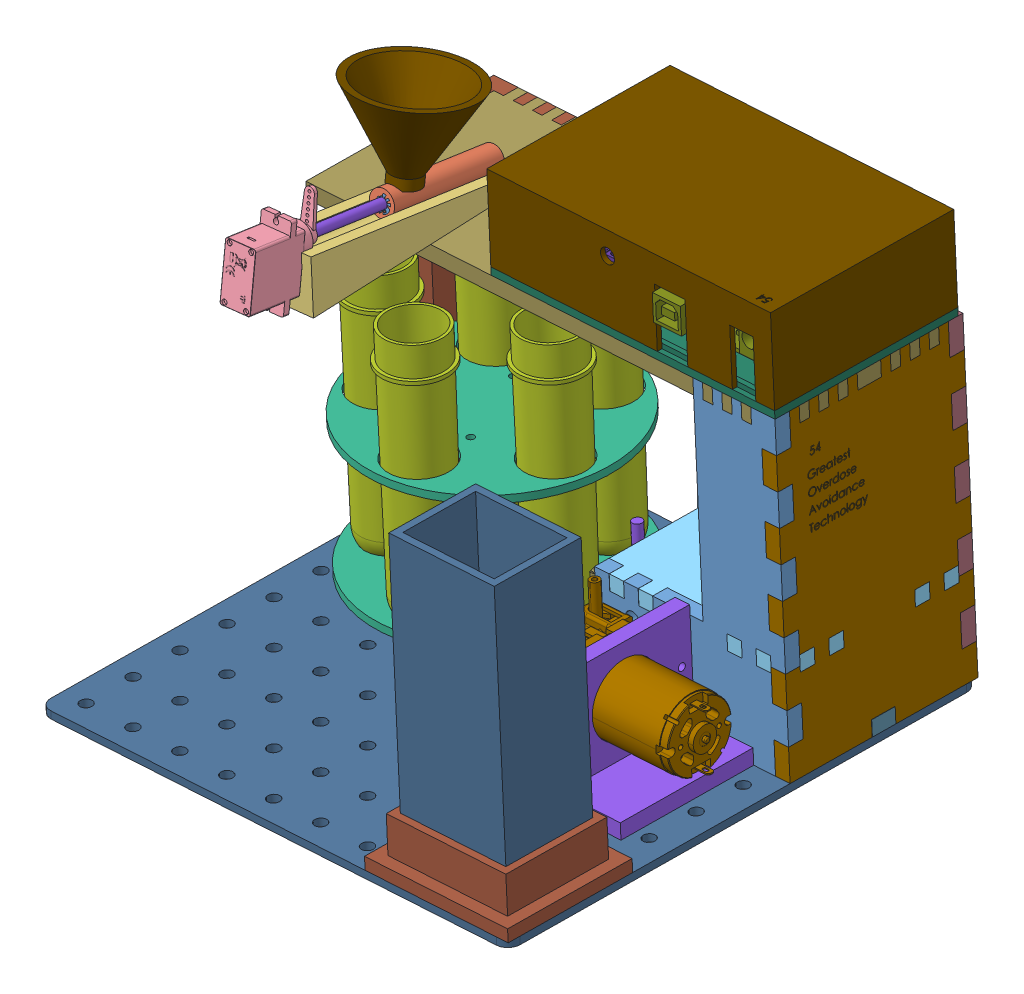
SolidWorks assembly Goat.forEdit4, configuration Default. Lengths in mm.
Overall size (207.7 193.28 201.45).
58 component instances, 40 part files, 115 mates.
Components (placement in the parent):
- 054_10T_NOPRINT_N3-1: 054_10T_NOPRINT_N3 [Default] at (24.5852 63.532 95.5991) x (0.998194 0.060061 -0.000979) z (0.060068 -0.998139 0.010543) size (12 11.58 6) (hidden)
- 054_20T_NOPRINT_N1-1: 054_20T_NOPRINT_N1 [Default] at (17.3412 70.7712 71.3424) x (0.976966 0.060954 0.204504) z (0.060068 -0.998139 0.010543) size (22 22 5.85) (hidden)
- 054_40T_NOPRINT_N2-1: 054_40T_NOPRINT_N2 [Default] at (17.8167 62.8694 71.4259) x (0.478271 0.03805 0.877387) z (0.060068 -0.998139 0.010543) size (42 42 5.85) (hidden)
- 054_50T_NOPRINT_N2-1: 054_50T_NOPRINT_N2 [Default] at (-14.9305 68.9822 85.8339) x (0.998003 0.06026 0.018945) z (0.060068 -0.998139 0.010543) size (52 51.94 5.85) (hidden)
- 054_30T_NOPRINT_N1-1: 054_30T_NOPRINT_N1 [Default] at (-29.6575 61.3354 72.298) x (0.998003 0.06026 0.018945) z (0.060068 -0.998139 0.010543) size (32 31.89 5.85) (hidden)
- DCMotor1-1: DCMotor1 [Default] at (22.0529 105.6116 95.1547) x (0.998194 0.060061 -0.000979) z (0.060068 -0.998139 0.010543) size (24 24 48.5) (hidden)
- 054_Bushing_NOPRINT_n1-1: 054_Bushing_NOPRINT_n1 [Default] at (25.0222 56.2699 95.6758) x (0.998194 0.060061 -0.000979) z (-0.060068 0.998139 -0.010543) size (8 7.5 8) (hidden)
- 054_10T_NOPRINT_N3-2: 054_10T_NOPRINT_N3 [Default] at (-14.5337 62.3892 85.9035) x (0.998003 0.06026 0.018945) z (0.060068 -0.998139 0.010543) size (12 11.58 6) (hidden)
- 054_10T_NOPRINT_N3-3: 054_10T_NOPRINT_N3 [Default] at (-29.2271 54.1839 72.3736) x (0.998003 0.06026 0.018945) z (0.060068 -0.998139 0.010543) size (12 11.58 6) (hidden)
- 054_40T_NOPRINT_N2-2: 054_40T_NOPRINT_N2 [Default] at (-47.3526 53.2765 89.7404) x (0.996292 0.060601 0.061065) z (0.060068 -0.998139 0.010543) size (42 42 5.85) (hidden)
- 054_Shaft_NOPRINT_N4-1: 054_Shaft_NOPRINT_N4 [Default] at (-48.9826 80.3621 89.4543) x (0.996292 0.060601 0.061065) z (0.060068 -0.998139 0.010543) size (4 4 40) (hidden)
- 054_Shaft_NOPRINT_N4-2: 054_Shaft_NOPRINT_N4 [Default] at (-30.8536 81.2115 72.0881) x (0.996135 0.060618 0.06356) z (0.060068 -0.998139 0.010543) size (4 4 40) (hidden)
- 054_Shaft_NOPRINT_N4-3: 054_Shaft_NOPRINT_N4 [Default] at (16.5513 83.8967 71.2038) x (0.998194 0.060061 -0.000979) z (0.060068 -0.998139 0.010543) size (4 4 40) (hidden)
- 054_Shaft_NOPRINT_N4-4: 054_Shaft_NOPRINT_N4 [Default] at (-15.7288 82.2476 85.6938) x (0.996135 0.060618 0.06356) z (0.060068 -0.998139 0.010543) size (4 4 40) (hidden)
- 054_50T_NOPRINT_N2-2: 054_50T_NOPRINT_N2 [Default] at (-88.9036 53.0779 108.5526) x (0.998194 0.060061 -0.000979) z (0.060068 -0.998139 0.010543) size (52 51.94 5.85) (hidden)
- 054_GearboxBack_AC_N1-1: 054_GearboxBack_AC_N1 [Default] at (40.1526 45.813 119.7207) x (0.000317 -0.010543 -0.999944) z (0.060068 -0.998139 0.010543) size (80 6.2 130) (hidden)
- 054_Pegboard_NOPRINT_N1-1: 054_Pegboard_NOPRINT_N1 [Default] at (-153.1553 32.4426 239.8071) x (0.998194 0.060068 -0.000317) z (-0.000317 0.010543 0.999944) size (200 3 200)
- 054_mastwall_AC_N2-1: 054_mastwall_AC_N2 [Default] at (-153.2832 33.6974 74.7786) x (0.000317 -0.010543 -0.999944) z (0.998194 0.060068 -0.000317) size (35 130 6.2)
- 054_topofmast_AC_N1-1: 054_topofmast_AC_N1 [Default] at (-160.7338 157.7415 118.4769) x (0.998194 0.060068 -0.000317) z (-0.000317 0.010543 0.999944) size (200 6.2 80)
- 054_mastwall_AC_N2-2: 054_mastwall_AC_N2 [Default] at (-126.1501 165.1885 38.4049) x (-0.998194 -0.060068 0.000317) z (-0.000317 0.010543 0.999944) size (35 130 6.2)
- 054_bracket_AC_N1-1: 054_bracket_AC_N1 [Default] at (-153.2892 33.6971 74.7846) x (0.998194 0.060068 -0.000317) z (-0.000317 0.010543 0.999944) size (35 6.2 35)
- 054_Peg_NOPRINT_N2-1: 054_Peg_NOPRINT_N2 [Default] at (-143.7859 42.2193 49.6964) x (0.99555 0.060673 0.07211) z (0.072615 -0.006165 -0.997341) size (6 11.2 6) (hidden)
- 054_Peg_NOPRINT_N2-2: 054_Peg_NOPRINT_N2 [Default] at (-123.8283 43.6315 69.6889) x (-0.839619 -0.04481 0.541325) z (0.539845 0.041368 0.840748) size (6 11.2 6) (hidden)
- 054_ArduinoHousingBottom_NOPRINT_N1-1: 054_ArduinoHousingBottom_NOPRINT_N1 [Default] at (-82.2489 168.6753 118.3865) x (0.998194 0.060068 -0.000317) z (-0.000317 0.010543 0.999944) size (121 13 78)
- 054_ArduinoUno_NOPRINT_N1-1: 054_ArduinoUno_NOPRINT_N1 [Default] at (32.4637 187.8519 47.2918) x (-0.006473 -0.010951 -0.999919) z (0.998173 0.059994 -0.007119) size (74.93 14.99 53.34)
- 054_Motorshield_NOPRINT_N1-1: 054_Motorshield_NOPRINT_N1 [Default] at (-28.0105 286.5986 113.2485) x (-0.013066 -0.011347 -0.99985) z (0.998109 0.059921 -0.013723) size (69.12 16.7 53.08)
- 054_ArduinoHousingTop_NOPRINT_N1-1: 054_ArduinoHousingTop_NOPRINT_N1 [Default] at (-84.5067 205.7822 39.9902) x (0.998194 0.060068 -0.000317) z (0.000317 -0.010543 -0.999944) size (121 35 78)
- 054_GearboxSide2_AC_N1-1: 054_GearboxSide2_AC_N1 [Default] at (-142.4309 40.1158 113.5226) x (0.998194 0.060068 -0.000317) z (-0.000317 0.010543 0.999944) size (81.25 130 6.2)
- 054_BearingInnerRing_NOPRINT_N1-1: 054_BearingInnerRing_NOPRINT_N1 [Default] at (-88.321 43.396 108.6549) x (0.060068 -0.998139 0.010543) z (0.984951 0.060982 0.161717) size (8.2 10 10)
- 054_BearingOuterRing_NOPRINT_N1-1: 054_BearingOuterRing_NOPRINT_N1 [Default] at (-88.321 43.396 108.6549) x (0.060068 -0.998139 0.010543) z (-0.60772 -0.028189 0.793651) size (8.2 19 19)
- 054_Bearing_NOPRINT_N5-1: 054_Bearing_NOPRINT_N5 [Default] at (-91.0396 43.8634 102.7287) x (0.060068 -0.998139 0.010543) z (0.984951 0.060982 0.161717) size (6 6 6)
- 054_Bearing_NOPRINT_N5-2: 054_Bearing_NOPRINT_N5 [Default] at (-83.1204 44.5298 104.8264) x (0.112171 -0.993333 -0.0266) z (0.981406 0.106549 0.159653) size (6 6 6)
- 054_Bearing_NOPRINT_N5-3: 054_Bearing_NOPRINT_N5 [Default] at (-82.9858 44.2937 112.2975) x (0.177726 -0.976919 0.118503) z (0.962907 0.197482 0.183878) size (6 6 6)
- 054_Bearing_NOPRINT_N5-4: 054_Bearing_NOPRINT_N5 [Default] at (-94.8595 43.996 108.9916) x (0.060068 -0.998139 0.010543) z (0.984951 0.060982 0.161717) size (6 6 6)
- 054_Bearing_NOPRINT_N5-5: 054_Bearing_NOPRINT_N5 [Default] at (-89.7183 43.105 115.0022) x (0.060068 -0.998139 0.010543) z (0.984951 0.060982 0.161717) size (6 6 6)
- 054_GearBoxRoof_AC_N1-1: 054_GearBoxRoof_AC_N1 [Default] at (-36.8971 77.196 39.3609) x (0.998194 0.060068 -0.000317) z (-0.000317 0.010543 0.999944) size (111.2 6.2 80)
- 054_Rack_NOPRINT_N1-1: 054_Rack_NOPRINT_N1 [Default] at (-92.1503 107.0273 107.9828) x (-0.409596 -0.034278 -0.911623) z (-0.060068 0.998139 -0.010543) size (100 100 56.8)
- 054_TestTube_NOPRINT_N5-1: 054_TestTube_NOPRINT_N5 [Default] at (-120.6243 48.9967 122.9583) x (-0.577063 -0.026105 0.816283) z (-0.060068 0.998139 -0.010543) size (27 27 107)
- 054_TestTube_NOPRINT_N5-2: 054_TestTube_NOPRINT_N5 [Default] at (-84.9753 51.3576 143.3663) x (0.927461 0.051903 -0.3703) z (-0.060068 0.998139 -0.010543) size (27 27 107)
- 054_TestTube_NOPRINT_N5-3: 054_TestTube_NOPRINT_N5 [Default] at (-54.5625 52.8956 115.6968) x (0.99814 0.060171 0.009807) z (-0.060068 0.998139 -0.010543) size (27 27 107)
- 054_TestTube_NOPRINT_N5-4: 054_TestTube_NOPRINT_N5 [Default] at (-71.4153 51.4852 78.1881) x (-0.9685 -0.060834 -0.241469) z (-0.060068 0.998139 -0.010543) size (27 27 107)
- 054_TestTube_NOPRINT_N5-5: 054_TestTube_NOPRINT_N5 [Default] at (-112.2438 49.0756 82.676) x (0.998106 0.060199 0.012641) z (-0.060068 0.998139 -0.010543) size (27 27 107)
- 054_PumpHolder_NOPRINT_N1-1: 054_PumpHolder_NOPRINT_N1 [Default] at (-3.0721 89.9938 119.2412) x (0.998194 0.060068 -0.000317) z (0.000317 -0.010543 -0.999944) size (31.2 46.7 56.5)
- 054_Pump_NOPRINT_N1-1: 054_Pump_NOPRINT_N1 [Default] at (-9.2228 107.9034 205.5236) x (0.998194 0.060068 -0.000317) z (0.000317 -0.010543 -0.999944) size (65.53 50.12 56.36)
- 054_Reservoir_NOPRINT_N1-1: 054_Reservoir_NOPRINT_N1 [Default] at (-6.5984 44.1827 231.7293) x (0.998194 0.060068 -0.000317) z (-0.000317 0.010543 0.999944) size (45 120 37)
- 054_ResevoireHolder_NOPRINT_N1-2: 054_ResevoireHolder_NOPRINT_N1 [Default] at (-14.5865 43.7865 239.7314) x (0.998194 0.060068 -0.000317) z (-0.000317 0.010543 0.999944) size (61 20 53)
- 054_LimitSwitch_NOPRINT_N1-1: 054_LimitSwitch_NOPRINT_N1 [Default] at (-28.6901 52.3163 103.2571) x (0.000317 -0.010543 -0.999944) z (0.998194 0.060068 -0.000317) size (21.33 6.06 18.84)
- 054_GearboxSide1_AC_N1-1: 054_GearboxSide1_AC_N1 [Default] at (-142.3991 39.1994 39.7281) x (0.998194 0.060068 -0.000317) z (-0.000317 0.010543 0.999944) size (111.25 130 6.2)
- 054_GearboxBottom1_AC_N1-2: 054_GearboxBottom1_AC_N1 [Default] at (120.8732 55.5086 -10.3311) x (-0.998194 -0.060068 0.000317) z (0.060068 -0.998139 0.010543) size (27.55 13.89 6.2)
- 054_GearboxBottom2_AC_N1-2: 054_GearboxBottom2_AC_N1 [Default] at (120.8732 55.5086 -10.3311) x (-0.998194 -0.060068 0.000317) z (-0.000317 0.010543 0.999944) size (43.38 6.2 21.84)
- 054_GearboxBottom3_AC_N1-2: 054_GearboxBottom3_AC_N1 [Default] at (120.8732 55.5079 -10.3969) x (-0.998194 -0.060068 0.000317) z (0.060068 -0.998139 0.010543) size (22.36 20.08 6.2)
- 054_GearboxBottom4_AC_N1-2: 054_GearboxBottom4_AC_N1 [Default] at (120.8732 55.5086 -10.3311) x (-0.998194 -0.060068 0.000317) z (0.060068 -0.998139 0.010543) size (29.6 29.16 6.2)
- 054_NewPowderFunnel_3D_N1-1: 054_NewPowderFunnel_3D_N1 [Default] at (-120.3035 167.9582 80.5979) x (0.056658 0.009583 0.998348) z (-0.9966 -0.059372 0.057129) size (46.29 39.16 47)
- 054_PowderWormDrive_3D_N1-1: 054_PowderWormDrive_3D_N1 [Default] at (-120.2589 168.3597 81.7939) x (0.056658 0.009583 0.998348) z (-0.9966 -0.059372 0.057129) size (50.91 15.58 7)
- 054_PowderHousing_3D_N1-1: 054_PowderHousing_3D_N1 [Default] at (-120.3157 168.1313 80.5662) x (0.056658 0.009583 0.998348) z (-0.9966 -0.059372 0.057129) size (51 18.68 10.46)
- 054_PowderStand_NOPRINT_N1-1: 054_PowderStand_NOPRINT_N1 [Default] at (-110.5271 172.9722 81.3135) x (0.056397 0.013939 0.998311) z (-0.9966 -0.059372 0.057129) size (90 21.84 20)
- 054_Shaft_NOPRINT_N4-5: 054_Shaft_NOPRINT_N4 [Default] at (-118.7121 180.9729 121.8857) x (-0.1149 -0.97564 0.186881) z (0.04541 0.182772 0.982106) size (4 4 40)
- Servo_SG90 - Updated-1: Servo_SG90 - Updated [Default] at (-142.9566 195.1026 199.9548) x (0.068751 -0.981361 0.179454) z (0.9966 0.059372 -0.057129) size (37.25 31.75 12.21)
Mates (geometry in assembly coordinates):
- Concentric4: concentric anti-aligned: cylinder of 054_Rack_NOPRINT_N1-1 through (-124.0103 105.2619 122.364) axis (-0.060068 0.998139 -0.010543) radius 12.5; cone of 054_TestTube_NOPRINT_N5-1 through (-123.8379 102.3971 122.3943) axis (0.060068 -0.998139 0.010543)
- Concentric5: concentric anti-aligned: cylinder of 054_Rack_NOPRINT_N1-1 through (-88.3613 107.6228 142.772) axis (-0.060068 0.998139 -0.010543) radius 12.5; cone of 054_TestTube_NOPRINT_N5-2 through (-88.1889 104.758 142.8023) axis (0.060068 -0.998139 0.010543)
- Coincident3: coincident aligned: plane of 054_TestTube_NOPRINT_N5-1 through (-127.0515 155.7975 121.8303) normal (-0.060068 0.998139 -0.010543); plane of 054_TestTube_NOPRINT_N5-2 through (-91.4025 158.1584 142.2382) normal (-0.060068 0.998139 -0.010543)
- Concentric6: concentric anti-aligned: cylinder of 054_Rack_NOPRINT_N1-1 through (-57.9485 109.1608 115.1024) axis (-0.060068 0.998139 -0.010543) radius 12.5; cone of 054_TestTube_NOPRINT_N5-3 through (-57.7761 106.296 115.1327) axis (0.060068 -0.998139 0.010543)
- Coincident9: coincident aligned: plane of 054_TestTube_NOPRINT_N5-2 through (-91.4025 158.1584 142.2382) normal (-0.060068 0.998139 -0.010543); plane of 054_TestTube_NOPRINT_N5-3 through (-60.9897 159.6964 114.5687) normal (-0.060068 0.998139 -0.010543)
- Concentric7: concentric anti-aligned: cylinder of 054_Rack_NOPRINT_N1-1 through (-74.8014 107.7504 77.5938) axis (-0.060068 0.998139 -0.010543) radius 12.5; cone of 054_TestTube_NOPRINT_N5-4 through (-74.6289 104.8856 77.624) axis (0.060068 -0.998139 0.010543)
- Coincident10: coincident aligned: plane of 054_TestTube_NOPRINT_N5-3 through (-60.9897 159.6964 114.5687) normal (-0.060068 0.998139 -0.010543); plane of 054_TestTube_NOPRINT_N5-4 through (-77.8426 158.286 77.06) normal (-0.060068 0.998139 -0.010543)
- Concentric8: concentric anti-aligned: cylinder of 054_Rack_NOPRINT_N1-1 through (-115.6298 105.3408 82.0817) axis (-0.060068 0.998139 -0.010543) radius 12.5; cone of 054_TestTube_NOPRINT_N5-5 through (-115.4574 102.476 82.1119) axis (0.060068 -0.998139 0.010543)
- Coincident12: coincident aligned: plane of 054_TestTube_NOPRINT_N5-4 through (-77.8426 158.286 77.06) normal (-0.060068 0.998139 -0.010543); plane of 054_TestTube_NOPRINT_N5-5 through (-118.671 155.8764 81.5479) normal (-0.060068 0.998139 -0.010543)
- Concentric9: concentric aligned: cylinder of 054_PumpHolder_NOPRINT_N1-1 through (4.3241 70.4517 147.7011) axis (-0.998194 -0.060068 0.000317) radius 14.2; cylinder of 054_Pump_NOPRINT_N1-1 through (35.917 72.3529 147.6911) axis (-0.998194 -0.060068 0.000317) radius 14
- Parallel2: parallel aligned: plane of 054_PumpHolder_NOPRINT_N1-1 through (3.1167 90.3662 119.2392) normal (-0.060068 0.998139 -0.010543); plane of 054_Pump_NOPRINT_N1-1 through (-6.2507 90.0739 156.7914) normal (-0.060068 0.998139 -0.010543)
- Coincident17: coincident anti-aligned: plane of 054_PumpHolder_NOPRINT_N1-1 through (-3.0721 89.9938 119.2412) normal (-0.998194 -0.060068 0.000317); plane of 054_Pump_NOPRINT_N1-1 through (-1.8647 70.0793 147.7031) normal (0.998194 0.060068 -0.000317)
- Coincident23: coincident anti-aligned: plane of 054_Reservoir_NOPRINT_N1-1 through (-6.7786 47.1771 231.6977) normal (-0.000317 0.010543 0.999944); plane of 054_ResevoireHolder_NOPRINT_N1-2 through (-7.7997 64.1454 231.5184) normal (0.000317 -0.010543 -0.999944)
- Coincident24: coincident anti-aligned: plane of 054_Reservoir_NOPRINT_N1-1 through (-6.7786 47.1771 231.6977) normal (-0.998194 -0.060068 0.000317); plane of 054_ResevoireHolder_NOPRINT_N1-2 through (-7.788 63.7553 194.5205) normal (0.998194 0.060068 -0.000317)
- Coincident56: coincident aligned: plane of 054_GearboxBottom1_AC_N1-2 through (121.2456 49.3202 -10.2657) normal (0.060068 -0.998139 0.010543); plane of 054_GearboxBottom2_AC_N1-2 through (121.2456 49.3202 -10.2657) normal (0.060068 -0.998139 0.010543)
- Coincident57: coincident aligned: plane of 054_GearboxBottom2_AC_N1-2 through (121.2456 49.3202 -10.2657) normal (0.060068 -0.998139 0.010543); plane of 054_GearboxBottom3_AC_N1-2 through (121.2456 49.3195 -10.3315) normal (0.060068 -0.998139 0.010543)
- Coincident58: coincident aligned: plane of 054_GearboxBottom4_AC_N1-2 through (121.2456 49.3202 -10.2657) normal (0.060068 -0.998139 0.010543); plane of 054_GearboxBottom3_AC_N1-2 through (121.2456 49.3195 -10.3315) normal (0.060068 -0.998139 0.010543)
- Coincident60: coincident anti-aligned: plane of 054_GearboxBottom4_AC_N1-2 through (86.8297 46.9018 -43.1406) normal (0.722178 0.050747 0.689843); plane of 054_GearboxBottom3_AC_N1-2 through (86.8626 46.9034 -43.1751) normal (-0.722178 -0.050747 -0.689843)
- Coincident61: coincident aligned: plane of 054_GearboxBottom4_AC_N1-2 through (11.5974 43.9382 104.918) normal (0.689094 0.033823 -0.723882); plane of 054_GearboxBottom3_AC_N1-2 through (11.5646 43.9359 104.8866) normal (0.689094 0.033823 -0.723882)
- Coincident62: coincident anti-aligned: plane of 054_GearboxBottom2_AC_N1-2 through (11.5974 43.9382 104.918) normal (-0.689094 -0.033823 0.723882); plane of 054_GearboxBottom3_AC_N1-2 through (11.5646 43.9359 104.8866) normal (0.689094 0.033823 -0.723882)
- Coincident63: coincident aligned: plane of 054_GearboxBottom2_AC_N1-2 through (135.8433 50.5236 20.4985) normal (0.428423 0.035319 0.902888); plane of 054_GearboxBottom3_AC_N1-2 through (135.8688 50.525 20.4863) normal (0.428423 0.035319 0.902888)
- Coincident64: coincident anti-aligned: plane of 054_GearboxBottom1_AC_N1-2 through (135.8433 50.5236 20.4985) normal (-0.428423 -0.035319 -0.902888); plane of 054_GearboxBottom2_AC_N1-2 through (135.8433 50.5236 20.4985) normal (0.428423 0.035319 0.902888)
- Coincident65: coincident aligned: plane of 054_GearboxBottom1_AC_N1-2 through (81.3791 47.99 90.9419) normal (0.366472 0.012227 -0.930349); plane of 054_GearboxBottom2_AC_N1-2 through (81.3791 47.99 90.9419) normal (0.366472 0.012227 -0.930349)
- Concentric3: concentric: cylinder of 054_10T_NOPRINT_N3-1 through (24.5852 63.532 95.5991) axis (0.060068 -0.998139 0.010543) radius 2; circle of 054_Bushing_NOPRINT_n1-1
- Concentric10: concentric: cylinder of 054_10T_NOPRINT_N3-1 through (24.5852 63.532 95.5991) axis (0.060068 -0.998139 0.010543) radius 2; cylinder of DCMotor1-1 through (23.8849 75.1684 95.4762) axis (0.060068 -0.998139 0.010543) radius 1
- Lock13: lock: unknown of 054_10T_NOPRINT_N3-1; unknown of 054_Bushing_NOPRINT_n1-1
- Coincident71: coincident: plane of 054_10T_NOPRINT_N3-1 through (24.5702 63.7816 95.5965) normal (-0.060068 0.998139 -0.010543); plane of 054_40T_NOPRINT_N2-1 through (17.8017 63.1189 71.4232) normal (-0.060068 0.998139 -0.010543)
- Concentric24: concentric: cylinder of 054_20T_NOPRINT_N1-1 through (17.3412 70.7712 71.3424) axis (0.060068 -0.998139 0.010543) radius 2; cylinder of 054_Shaft_NOPRINT_N4-3 through (18.954 43.9711 71.6255) axis (-0.060068 0.998139 -0.010543) radius 2
- Lock24: lock: unknown of 054_20T_NOPRINT_N1-1; unknown of 054_Shaft_NOPRINT_N4-3
- Coincident4: coincident: plane of 054_20T_NOPRINT_N1-1 through (17.3262 71.0208 71.3398) normal (-0.060068 0.998139 -0.010543); plane of 054_50T_NOPRINT_N2-1 through (-14.9455 69.2317 85.8312) normal (-0.060068 0.998139 -0.010543)
- Concentric23: concentric: cylinder of 054_40T_NOPRINT_N2-1 through (17.8167 62.8694 71.4259) axis (0.060068 -0.998139 0.010543) radius 2; cylinder of 054_Shaft_NOPRINT_N4-3 through (18.954 43.9711 71.6255) axis (-0.060068 0.998139 -0.010543) radius 2
- Lock25: lock: unknown of 054_40T_NOPRINT_N2-1; unknown of 054_Shaft_NOPRINT_N4-3
- Concentric20: concentric: cylinder of 054_50T_NOPRINT_N2-1 through (-14.9305 68.9822 85.8339) axis (0.060068 -0.998139 0.010543) radius 2; cylinder of 054_Shaft_NOPRINT_N4-4 through (-13.3261 42.3221 86.1155) axis (-0.060068 0.998139 -0.010543) radius 2
- Lock23: lock: unknown of 054_50T_NOPRINT_N2-1; unknown of 054_Shaft_NOPRINT_N4-4
- Concentric13: concentric: cylinder of 054_30T_NOPRINT_N1-1 through (-29.6575 61.3354 72.298) axis (0.060068 -0.998139 0.010543) radius 2; cylinder of 054_Shaft_NOPRINT_N4-2 through (-28.4509 41.286 72.5098) axis (-0.060068 0.998139 -0.010543) radius 2
- Lock19: lock: unknown of 054_30T_NOPRINT_N1-1; unknown of 054_Shaft_NOPRINT_N4-2
- Coincident7: coincident: plane of 054_30T_NOPRINT_N1-1 through (-29.6725 61.5849 72.2954) normal (-0.060068 0.998139 -0.010543); plane of 054_10T_NOPRINT_N3-2 through (-14.5487 62.6388 85.9009) normal (-0.060068 0.998139 -0.010543)
- Lock12: lock: unknown of DCMotor1-1; unknown of 054_Bushing_NOPRINT_n1-1
- Concentric18: concentric: cylinder of 054_10T_NOPRINT_N3-2 through (-14.5337 62.3892 85.9035) axis (0.060068 -0.998139 0.010543) radius 2; cylinder of 054_Shaft_NOPRINT_N4-4 through (-13.3261 42.3221 86.1155) axis (-0.060068 0.998139 -0.010543) radius 2
- Lock22: lock: unknown of 054_10T_NOPRINT_N3-2; unknown of 054_Shaft_NOPRINT_N4-4
- Concentric11: concentric: cylinder of 054_10T_NOPRINT_N3-3 through (-29.2271 54.1839 72.3736) axis (0.060068 -0.998139 0.010543) radius 2; cylinder of 054_Shaft_NOPRINT_N4-2 through (-28.4509 41.286 72.5098) axis (-0.060068 0.998139 -0.010543) radius 2
- Lock18: lock: unknown of 054_10T_NOPRINT_N3-3; unknown of 054_Shaft_NOPRINT_N4-2
- Coincident72: coincident: plane of 054_10T_NOPRINT_N3-3 through (-29.2421 54.4334 72.3709) normal (-0.060068 0.998139 -0.010543); plane of 054_40T_NOPRINT_N2-2 through (-47.3676 53.5261 89.7378) normal (-0.060068 0.998139 -0.010543)
- Concentric25: concentric: cylinder of 054_40T_NOPRINT_N2-2 through (-47.3526 53.2765 89.7404) axis (0.060068 -0.998139 0.010543) radius 2; cylinder of 054_Shaft_NOPRINT_N4-1 through (-46.5798 40.4365 89.8761) axis (-0.060068 0.998139 -0.010543) radius 2
- Lock17: lock: unknown of 054_40T_NOPRINT_N2-2; unknown of 054_Shaft_NOPRINT_N4-1
- Parallel5: parallel aligned: plane of 054_40T_NOPRINT_N2-2 through (-47.3676 53.5261 89.7378) normal (-0.060068 0.998139 -0.010543); plane of 054_50T_NOPRINT_N2-2 through (-88.9186 53.3275 108.55) normal (-0.060068 0.998139 -0.010543)
- Coincident33: coincident: plane of 054_GearboxBack_AC_N1-1 through (46.3414 46.1854 119.7187) normal (0.060068 -0.998139 0.010543); plane of 054_Pegboard_NOPRINT_N1-1 through (-153.3355 35.4371 239.7755) normal (-0.060068 0.998139 -0.010543)
- Coincident34: coincident: plane of 054_GearboxBack_AC_N1-1 through (46.3414 46.1854 119.7187) normal (0.998194 0.060068 -0.000317); plane of 054_Pegboard_NOPRINT_N1-1 through (46.3034 47.4506 239.7121) normal (0.998194 0.060068 -0.000317)
- Coincident48: coincident: plane of 054_GearboxBack_AC_N1-1 through (46.3434 46.1201 113.5191) normal (-0.000317 0.010543 0.999944); plane of 054_GearboxSide2_AC_N1-1 through (-142.4309 40.1158 113.5226) normal (0.000317 -0.010543 -0.999944)
- Coincident49: coincident: plane of 054_GearboxBack_AC_N1-1 through (46.3414 46.1854 119.7187) normal (0.998194 0.060068 -0.000317); plane of 054_GearboxSide2_AC_N1-1 through (46.0203 51.5216 119.6624) normal (0.998194 0.060068 -0.000317)
- Coincident59: coincident anti-aligned: plane of 054_GearboxBack_AC_N1-1 through (46.3434 46.1201 113.5191) normal (0.000317 -0.010543 -0.999944); plane of 054_GearBoxRoof_AC_N1-1 through (-37.2929 84.1625 113.0915) normal (-0.000317 0.010543 0.999944)
- Coincident74: coincident anti-aligned: plane of 054_GearboxBack_AC_N1-1 through (44.1309 82.9169 119.3308) normal (-0.060068 0.998139 -0.010543); plane of 054_GearBoxRoof_AC_N1-1 through (-36.8971 77.196 39.3609) normal (0.060068 -0.998139 0.010543)
- Coincident75: coincident aligned: plane of 054_GearboxBack_AC_N1-1 through (46.3414 46.1854 119.7187) normal (0.998194 0.060068 -0.000317); plane of 054_GearBoxRoof_AC_N1-1 through (43.7839 88.262 39.2698) normal (0.998194 0.060068 -0.000317)
- Concentric29: concentric aligned: cylinder of 054_Pegboard_NOPRINT_N1-1 through (-143.1131 31.0402 49.8145) axis (-0.060068 0.998139 -0.010543) radius 2.5; cylinder of 054_Peg_NOPRINT_N2-1 through (-143.1131 31.0402 49.8145) axis (-0.060068 0.998139 -0.010543) radius 2.475
- Coincident42: coincident aligned: plane of 054_Pegboard_NOPRINT_N1-1 through (-153.1553 32.4426 239.8071) normal (0.060068 -0.998139 0.010543); plane of 054_Peg_NOPRINT_N2-1 through (-143.1131 31.0402 49.8145) normal (0.060068 -0.998139 0.010543)
- Concentric31: concentric aligned: cylinder of 054_Pegboard_NOPRINT_N1-1 through (-123.1556 32.4524 69.807) axis (-0.060068 0.998139 -0.010543) radius 2.5; cylinder of 054_Peg_NOPRINT_N2-2 through (-123.1556 32.4524 69.807) axis (-0.060068 0.998139 -0.010543) radius 2.475
- Coincident45: coincident aligned: plane of 054_Pegboard_NOPRINT_N1-1 through (-153.1553 32.4426 239.8071) normal (0.060068 -0.998139 0.010543); plane of 054_Peg_NOPRINT_N2-2 through (-123.1556 32.4524 69.807) normal (0.060068 -0.998139 0.010543)
- Coincident47: coincident: plane of 054_Pegboard_NOPRINT_N1-1 through (-153.3355 35.4371 239.7755) normal (-0.060068 0.998139 -0.010543); plane of 054_GearboxSide2_AC_N1-1 through (-142.1117 34.845 119.7786) normal (0.060068 -0.998139 0.010543)
- Coincident78: coincident anti-aligned: plane of 054_50T_NOPRINT_N2-2 through (-88.9186 53.3275 108.55) normal (-0.060068 0.998139 -0.010543); plane of 054_Rack_NOPRINT_N1-1 through (-88.9186 53.3275 108.55) normal (0.060068 -0.998139 0.010543)
- Concentric33: concentric anti-aligned: cylinder of 054_50T_NOPRINT_N2-2 through (-88.9036 53.0779 108.5526) axis (0.060068 -0.998139 0.010543) radius 2; circle of 054_Rack_NOPRINT_N1-1
- Coincident79: coincident aligned: plane of 054_GearboxBack_AC_N1-1 through (46.3414 46.1854 119.7187) normal (0.998194 0.060068 -0.000317); plane of 054_GearboxSide1_AC_N1-1 through (46.052 50.6051 45.8679) normal (0.998194 0.060068 -0.000317)
- Coincident80: coincident anti-aligned: plane of 054_GearboxBack_AC_N1-1 through (46.3648 45.4074 45.9228) normal (0.000317 -0.010543 -0.999944); plane of 054_GearboxSide1_AC_N1-1 through (-142.4011 39.2647 45.9278) normal (-0.000317 0.010543 0.999944)
- Coincident81: coincident aligned: plane of 054_GearboxBack_AC_N1-1 through (46.3414 46.1854 119.7187) normal (0.998194 0.060068 -0.000317); plane of 054_GearboxBottom1_AC_N1-2 through (46.3826 44.8152 -10.2419) normal (0.998194 0.060068 -0.000317)
- Coincident82: coincident anti-aligned: plane of 054_GearboxBack_AC_N1-1 through (46.3557 45.7105 74.6712) normal (-0.000317 0.010543 0.999944); plane of 054_GearboxBottom1_AC_N1-2 through (121.2187 50.2154 74.6475) normal (0.000317 -0.010543 -0.999944)
- Coincident83: coincident anti-aligned: plane of 054_Pegboard_NOPRINT_N1-1 through (-153.3355 35.4371 239.7755) normal (-0.060068 0.998139 -0.010543); plane of 054_PumpHolder_NOPRINT_N1-1 through (5.9219 43.7531 119.7316) normal (0.060068 -0.998139 0.010543)
- Coincident84: coincident: plane of 054_Pegboard_NOPRINT_N1-1 through (-153.3355 35.4371 239.7755) normal (-0.060068 0.998139 -0.010543); plane of 054_ResevoireHolder_NOPRINT_N1-2 through (-14.5865 43.7865 239.7314) normal (0.060068 -0.998139 0.010543)
- Coincident85: coincident: plane of 054_Pegboard_NOPRINT_N1-1 through (-153.3355 35.4371 239.7755) normal (-0.000317 0.010543 0.999944); plane of 054_ResevoireHolder_NOPRINT_N1-2 through (-14.8868 48.7771 239.6787) normal (-0.000317 0.010543 0.999944)
- Coincident86: coincident: plane of 054_Pegboard_NOPRINT_N1-1 through (46.3034 47.4506 239.7121) normal (0.998194 0.060068 -0.000317); plane of 054_ResevoireHolder_NOPRINT_N1-2 through (46.003 52.4413 239.6593) normal (0.998194 0.060068 -0.000317)
- Coincident87: coincident: plane of 054_Pegboard_NOPRINT_N1-1 through (-153.3355 35.4371 239.7755) normal (-0.060068 0.998139 -0.010543); plane of 054_Reservoir_NOPRINT_N1-1 through (-6.5984 44.1827 231.7293) normal (0.060068 -0.998139 0.010543)
- Coincident88: coincident anti-aligned: plane of 054_Pegboard_NOPRINT_N1-1 through (-153.3355 35.4371 239.7755) normal (-0.060068 0.998139 -0.010543); plane of 054_GearboxBottom2_AC_N1-2 through (121.2456 49.3202 -10.2657) normal (0.060068 -0.998139 0.010543)
- Coincident91: coincident anti-aligned: plane of 054_GearboxSide2_AC_N1-1 through (-142.4328 40.1812 119.7222) normal (-0.000317 0.010543 0.999944); plane of 054_PumpHolder_NOPRINT_N1-1 through (3.1167 90.3662 119.2392) normal (0.000317 -0.010543 -0.999944)
- Coincident92: coincident anti-aligned: plane of 054_GearboxSide2_AC_N1-1 through (-142.4309 40.1158 113.5226) normal (0.000317 -0.010543 -0.999944); plane of 054_LimitSwitch_NOPRINT_N1-1 through (-32.0396 78.2678 113.1553) normal (-0.000317 0.010543 0.999944)
- Coincident93: coincident anti-aligned: plane of 054_GearBoxRoof_AC_N1-1 through (-36.8971 77.196 39.3609) normal (0.060068 -0.998139 0.010543); plane of 054_LimitSwitch_NOPRINT_N1-1 through (-32.0364 78.1624 103.1558) normal (-0.060068 0.998139 -0.010543)
- Coincident94: coincident anti-aligned: plane of 054_mastwall_AC_N2-1 through (-147.0931 34.0265 70.6669) normal (0.000317 -0.010543 -0.999944); plane of 054_topofmast_AC_N1-1 through (-161.0907 163.4121 69.2983) normal (-0.000317 0.010543 0.999944)
- Coincident25: coincident aligned: plane of 054_mastwall_AC_N2-1 through (-154.9032 163.8279 73.4061) normal (-0.060068 0.998139 -0.010543); plane of 054_topofmast_AC_N1-1 through (-161.1062 163.9299 118.4116) normal (-0.060068 0.998139 -0.010543)
- Coincident26: coincident aligned: plane of 054_mastwall_AC_N2-1 through (-153.2832 33.6974 74.7786) normal (-0.998194 -0.060068 0.000317); plane of 054_topofmast_AC_N1-1 through (-161.1062 163.9299 118.4116) normal (-0.998194 -0.060068 0.000317)
- Coincident29: coincident anti-aligned: plane of 054_topofmast_AC_N1-1 through (-130.278 165.7851 118.4018) normal (0.998194 0.060068 -0.000317); plane of 054_mastwall_AC_N2-2 through (-130.2546 165.007 44.6059) normal (-0.998194 -0.060068 0.000317)
- Coincident95: coincident anti-aligned: plane of 054_mastwall_AC_N2-2 through (-126.152 165.2539 44.6046) normal (-0.000317 0.010543 0.999944); plane of 054_topofmast_AC_N1-1 through (-161.0828 163.1519 44.6157) normal (0.000317 -0.010543 -0.999944)
- Coincident39: coincident aligned: plane of 054_topofmast_AC_N1-1 through (-161.1062 163.9299 118.4116) normal (-0.060068 0.998139 -0.010543); plane of 054_mastwall_AC_N2-2 through (-126.152 165.2539 44.6046) normal (-0.060068 0.998139 -0.010543)
- Coincident96: coincident anti-aligned: plane of 054_mastwall_AC_N2-2 through (-130.2546 165.007 44.6059) normal (-0.998194 -0.060068 0.000317); plane of 054_bracket_AC_N1-1 through (-122.8182 41.4374 45.9111) normal (0.998194 0.060068 -0.000317)
- Coincident43: coincident anti-aligned: plane of 054_mastwall_AC_N2-2 through (-118.7157 41.6843 45.9098) normal (0.060068 -0.998139 0.010543); plane of 054_bracket_AC_N1-1 through (-153.6616 39.8856 74.7193) normal (-0.060068 0.998139 -0.010543)
- Coincident44: coincident anti-aligned: plane of 054_mastwall_AC_N2-2 through (-126.152 165.2539 44.6046) normal (-0.000317 0.010543 0.999944); plane of 054_bracket_AC_N1-1 through (-118.7157 41.6843 45.9098) normal (0.000317 -0.010543 -0.999944)
- Coincident97: coincident: plane of 054_Pegboard_NOPRINT_N1-1 through (-153.3355 35.4371 239.7755) normal (-0.998194 -0.060068 0.000317); plane of 054_mastwall_AC_N2-1 through (-153.2832 33.6974 74.7786) normal (-0.998194 -0.060068 0.000317)
- Coincident99: coincident aligned: plane of 054_topofmast_AC_N1-1 through (-161.1062 163.9299 118.4116) normal (-0.060068 0.998139 -0.010543); plane of 054_GearboxSide1_AC_N1-1 through (-149.8971 163.825 44.6121) normal (-0.060068 0.998139 -0.010543)
- Coincident101: coincident aligned: plane of 054_Pegboard_NOPRINT_N1-1 through (-153.2721 33.3285 39.7866) normal (0.000317 -0.010543 -0.999944); plane of 054_mastwall_AC_N2-2 through (-126.1501 165.1885 38.4049) normal (0.000317 -0.010543 -0.999944)
- Coincident102: coincident anti-aligned: plane of 054_Pegboard_NOPRINT_N1-1 through (-153.3355 35.4371 239.7755) normal (-0.060068 0.998139 -0.010543); plane of 054_bracket_AC_N1-1 through (-153.2892 33.6971 74.7846) normal (0.060068 -0.998139 0.010543)
- Coincident1: coincident anti-aligned: plane of 054_ArduinoHousingBottom_NOPRINT_N1-1 through (-73.0414 182.0388 98.0474) normal (-0.060068 0.998139 -0.010543); plane of 054_ArduinoUno_NOPRINT_N1-1 through (6.1808 186.6149 79.9252) normal (0.060068 -0.998139 0.010543)
- Coincident2: coincident anti-aligned: plane of 054_ArduinoHousingBottom_NOPRINT_N1-1 through (-31.1013 184.0313 47.7369) normal (-0.060068 0.998139 -0.010543); plane of 054_Motorshield_NOPRINT_N1-1 through (-21.9136 185.2875 114.3186) normal (0.060068 -0.998139 0.010543)
- Coincident103: coincident anti-aligned: plane of 054_ArduinoHousingBottom_NOPRINT_N1-1 through (-82.4291 171.6697 118.3549) normal (-0.060068 0.998139 -0.010543); plane of 054_ArduinoHousingTop_NOPRINT_N1-1 through (-82.4044 170.8473 40.3592) normal (0.060068 -0.998139 0.010543)
- Coincident104: coincident aligned: plane of 054_ArduinoHousingBottom_NOPRINT_N1-1 through (-82.4291 171.6697 118.3549) normal (-0.000317 0.010543 0.999944); plane of 054_ArduinoHousingTop_NOPRINT_N1-1 through (-82.4291 171.6697 118.3549) normal (-0.000317 0.010543 0.999944)
- Coincident5: coincident aligned: plane of 054_ArduinoHousingBottom_NOPRINT_N1-1 through (38.3524 178.9379 118.3165) normal (0.998194 0.060068 -0.000317); plane of 054_ArduinoHousingTop_NOPRINT_N1-1 through (38.3771 178.1155 40.3209) normal (0.998194 0.060068 -0.000317)
- Coincident105: coincident anti-aligned: plane of 054_topofmast_AC_N1-1 through (-161.1062 163.9299 118.4116) normal (-0.060068 0.998139 -0.010543); plane of 054_ArduinoHousingBottom_NOPRINT_N1-1 through (-82.2489 168.6753 118.3865) normal (0.060068 -0.998139 0.010543)
- Coincident106: coincident aligned: plane of 054_ArduinoHousingTop_NOPRINT_N1-1 through (38.3771 178.1155 40.3209) normal (0.998194 0.060068 -0.000317); plane of 054_GearboxSide2_AC_N1-1 through (46.0203 51.5216 119.6624) normal (0.998194 0.060068 -0.000317)
- Coincident107: coincident aligned: plane of 054_ArduinoHousingTop_NOPRINT_N1-1 through (-82.4291 171.6697 118.3549) normal (-0.000317 0.010543 0.999944); plane of 054_GearboxSide2_AC_N1-1 through (-142.4328 40.1812 119.7222) normal (-0.000317 0.010543 0.999944)
- Concentric34: concentric anti-aligned: cylinder of 054_BearingInnerRing_NOPRINT_N1-1 through (-87.6087 31.5608 108.7799) axis (0.060068 -0.998139 0.010543) radius 5; cylinder of 054_BearingOuterRing_NOPRINT_N1-1 through (-88.9757 54.2763 108.54) axis (-0.060068 0.998139 -0.010543) radius 6
- Coincident108: coincident aligned: plane of 054_BearingInnerRing_NOPRINT_N1-1 through (-87.9126 39.303 107.7113) normal (0.060068 -0.998139 0.010543); plane of 054_BearingOuterRing_NOPRINT_N1-1 through (-83.3234 39.6281 112.3478) normal (0.060068 -0.998139 0.010543)
- Parallel1: parallel aligned: plane of 054_BearingInnerRing_NOPRINT_N1-1 through (-87.9126 39.303 107.7113) normal (0.060068 -0.998139 0.010543); plane of 054_BearingOuterRing_NOPRINT_N1-1 through (-83.3234 39.6281 112.3478) normal (0.060068 -0.998139 0.010543)
- Tangent1: tangent aligned: cylinder of 054_BearingOuterRing_NOPRINT_N1-1 through (-88.9757 54.2763 108.54) axis (-0.060068 0.998139 -0.010543) radius 9.5; sphere of 054_Bearing_NOPRINT_N5-2
- Tangent2: tangent aligned: cylinder of 054_BearingOuterRing_NOPRINT_N1-1 through (-88.9757 54.2763 108.54) axis (-0.060068 0.998139 -0.010543) radius 9.5; sphere of 054_Bearing_NOPRINT_N5-2
- Tangent3: tangent aligned: cylinder of 054_BearingOuterRing_NOPRINT_N1-1 through (-88.9757 54.2763 108.54) axis (-0.060068 0.998139 -0.010543) radius 9.5; sphere of 054_Bearing_NOPRINT_N5-1
- Tangent4: tangent aligned: cylinder of 054_BearingOuterRing_NOPRINT_N1-1 through (-88.9757 54.2763 108.54) axis (-0.060068 0.998139 -0.010543) radius 9.5; sphere of 054_Bearing_NOPRINT_N5-4
- Tangent5: tangent aligned: cylinder of 054_BearingOuterRing_NOPRINT_N1-1 through (-88.9757 54.2763 108.54) axis (-0.060068 0.998139 -0.010543) radius 9.5; sphere of 054_Bearing_NOPRINT_N5-5
- Tangent6: tangent aligned: cylinder of 054_BearingOuterRing_NOPRINT_N1-1 through (-88.9757 54.2763 108.54) axis (-0.060068 0.998139 -0.010543) radius 9.5; sphere of 054_Bearing_NOPRINT_N5-3
- Concentric35: concentric aligned: cylinder of 054_50T_NOPRINT_N2-2 through (-88.9036 53.0779 108.5526) axis (0.060068 -0.998139 0.010543) radius 2; cylinder of 054_BearingInnerRing_NOPRINT_N1-1 through (-87.6087 31.5608 108.7799) axis (0.060068 -0.998139 0.010543) radius 1
- Coincident109: coincident anti-aligned: plane of 054_50T_NOPRINT_N2-2 through (-88.5672 47.4884 108.6117) normal (0.060068 -0.998139 0.010543); plane of 054_BearingOuterRing_NOPRINT_N1-1 through (-83.816 47.8128 112.2614) normal (-0.060068 0.998139 -0.010543)
- Coincident110: coincident: plane of 054_NewPowderFunnel_3D_N1-1 through (-119.2356 183.4591 115.3379) normal (0.068751 -0.981361 0.179454); plane of 054_PowderHousing_3D_N1-1 through (-120.9157 176.6965 79) normal (-0.068751 0.981361 -0.179454)
- Concentric2: concentric: cylinder of 054_NewPowderFunnel_3D_N1-1 through (-119.0993 184.0074 118.2842) axis (-0.068751 0.981361 -0.179454) radius 6; cylinder of 054_PowderHousing_3D_N1-1 through (-119.1114 184.1804 118.2526) axis (0.068751 -0.981361 0.179454) radius 6.2
- Concentric1: concentric: circle of 054_PowderWormDrive_3D_N1-1; circle of 054_PowderHousing_3D_N1-1
- Coincident111: coincident: plane of 054_PowderWormDrive_3D_N1-1 through (-120.6647 173.1138 79.6551) normal (-0.04541 -0.182772 -0.982106); plane of 054_PowderHousing_3D_N1-1 through (-120.3157 168.1313 80.5662) normal (-0.04541 -0.182772 -0.982106)
- Concentric36: concentric anti-aligned: cylinder of 054_PowderWormDrive_3D_N1-1 through (-118.7121 180.9729 121.8857) axis (0.04541 0.182772 0.982106) radius 2.075; cylinder of 054_Shaft_NOPRINT_N4-5 through (-116.8957 188.2838 161.1699) axis (-0.04541 -0.182772 -0.982106) radius 2
- Coincident112: coincident anti-aligned: plane of 054_PowderWormDrive_3D_N1-1 through (-118.7121 180.9729 121.8857) normal (0.04541 0.182772 0.982106); plane of 054_Shaft_NOPRINT_N4-5 through (-118.7121 180.9729 121.8857) normal (-0.04541 -0.182772 -0.982106)
- Concentric37: concentric anti-aligned: cylinder of 054_PowderHousing_3D_N1-1 through (-120.608 173.3422 80.8828) axis (-0.04541 -0.182772 -0.982106) radius 5.0771; cylinder of 054_PowderStand_NOPRINT_N1-1 through (-120.6201 173.2934 80.6205) axis (0.04541 0.182772 0.982106) radius 5.5
- Concentric38: concentric anti-aligned: cylinder of 054_PowderHousing_3D_N1-1 through (-120.608 173.3422 80.8828) axis (-0.04541 -0.182772 -0.982106) radius 5.0771; cylinder of 054_PowderStand_NOPRINT_N1-1 through (-120.6201 173.2934 80.6205) axis (0.04541 0.182772 0.982106) radius 5.5
- Concentric39: concentric anti-aligned: circle of 054_Shaft_NOPRINT_N4-5; circle of Servo_SG90 - Updated-1
- Coincident113: coincident anti-aligned: plane of 054_topofmast_AC_N1-1 through (-161.1062 163.9299 118.4116) normal (-0.060068 0.998139 -0.010543); plane of 054_PowderStand_NOPRINT_N1-1 through (-130.076 165.4183 82.5233) normal (0.060068 -0.998139 0.010543)
